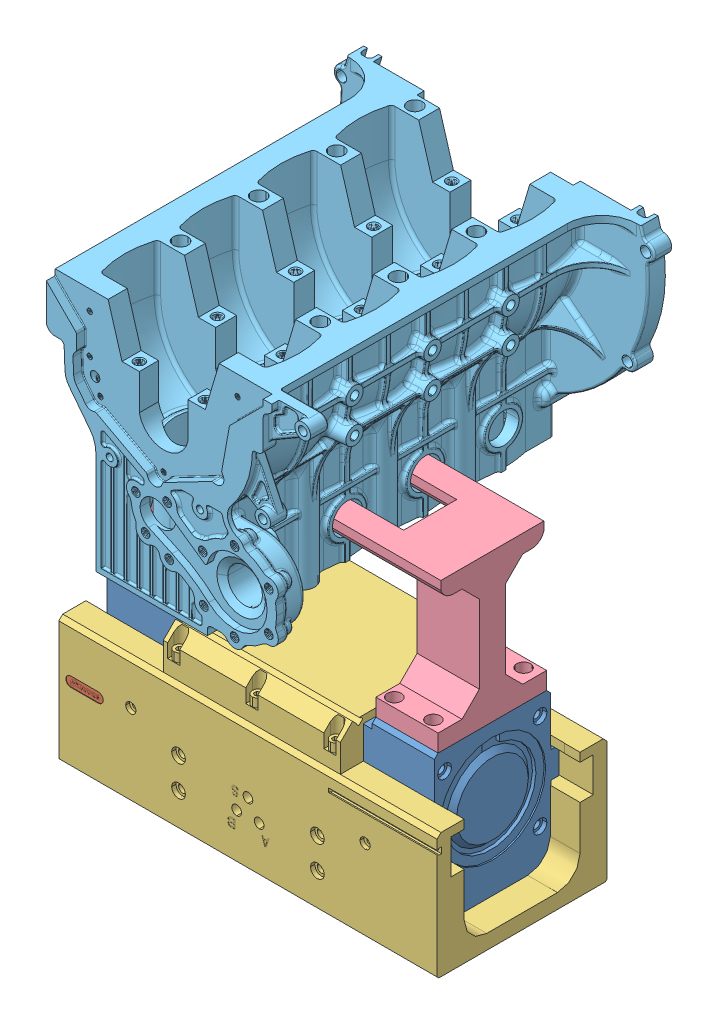
SolidWorks assembly SCHUNK_0302120_SPG_100_SDV_P__950ohne, configuration Default. Lengths in mm.
Overall size (436 582.06 410.5).
8 component instances, 6 part files, 25 mates.
Components (placement in the parent):
- SCHUNK_0302120_SPG_100_SDV_P__950ohne_3-1: SCHUNK_0302120_SPG_100_SDV_P__950ohne_3 [Default] at (-106.145 114.7 0.25) x (0 0 1) z (-1 0 0) size (154.2 173.7 174.7)
- SCHUNK_0302120_SPG_100_SDV_P__950ohne_3-2: SCHUNK_0302120_SPG_100_SDV_P__950ohne_3 [Default] at (96.355 114.7 0) x (0 0 -1) z (1 0 0) size (154.2 173.7 174.7)
- SCHUNK_0302120_SPG_100_SDV_P__950ohne_6-1: SCHUNK_0302120_SPG_100_SDV_P__950ohne_6 [Default] at (-188.35 86.7 97.3) x (-1 0 0) z (0 0 1) size (43 11 0.3)
- SCHUNK_0302120_SPG_100_SDV_P__950ohne_8-1: SCHUNK_0302120_SPG_100_SDV_P__950ohne_8 [Default] at origin size (436 191 196)
- griffa-1: griffa [Default] at (-157.645 356.6 45.25) x (0 0 -1) z (-1 0 0) size (125.01 170.71 140.85)
- griffa-2: griffa [Default] at (147.855 356.6 -45) x (0 0 1) z (1 0 0) size (125.01 170.71 140.85)
- XSR201_lavorato-1: XSR201_lavorato [Default] at (0 301.6755 0) x (0 1 0) z (-0.99865 0 -0.051938) size (110 140 140) (hidden)
- Head Motor-1: Head Motor [Default] at (-4.895 528.0542 135.25) x (-1 0 0) z (0 0 1) size (370.59 268.41 410.5)
Mates (geometry in assembly coordinates):
- Coincidente16: coincident anti-aligned: plane of SCHUNK_0302120_SPG_100_SDV_P__950ohne_3-1 through (-102 191.75 87.6) normal (1 0 0); plane of SCHUNK_0302120_SPG_100_SDV_P__950ohne_8-1 through (-102 145 150) normal (-1 0 0)
- Coincidente2: coincident anti-aligned: plane of SCHUNK_0302120_SPG_100_SDV_P__950ohne_3-2 through (102 191.75 -87.35) normal (-1 0 0); plane of SCHUNK_0302120_SPG_100_SDV_P__950ohne_8-1 through (102 192 150) normal (1 0 0)
- Coincidente6: coincident anti-aligned: plane of SCHUNK_0302120_SPG_100_SDV_P__950ohne_3-1 through (-193.495 134.45 67) normal (0 0 1); plane of SCHUNK_0302120_SPG_100_SDV_P__950ohne_8-1 through (200 182.4 67) normal (0 0 -1)
- Coincidente7: coincident anti-aligned: plane of SCHUNK_0302120_SPG_100_SDV_P__950ohne_3-2 through (183.705 187.3574 66.75) normal (0 0 1); plane of SCHUNK_0302120_SPG_100_SDV_P__950ohne_8-1 through (218 94.9 66.75) normal (0 0 -1)
- Coincidente8: coincident anti-aligned: plane of SCHUNK_0302120_SPG_100_SDV_P__950ohne_3-2 through (183.705 17.9 40.75) normal (0 -1 0); plane of SCHUNK_0302120_SPG_100_SDV_P__950ohne_8-1 through (218 17.9 40.75) normal (0 1 0)
- Coincidente9: coincident anti-aligned: plane of SCHUNK_0302120_SPG_100_SDV_P__950ohne_3-1 through (-193.495 17.9 -40.5) normal (0 -1 0); plane of SCHUNK_0302120_SPG_100_SDV_P__950ohne_8-1 through (218 17.9 40.75) normal (0 1 0)
- Coincidente10: coincident anti-aligned: plane of SCHUNK_0302120_SPG_100_SDV_P__950ohne_3-1 through (-193.495 191.6 62.7574) normal (0 1 0); plane of griffa-1 through (-157.645 191.6 45.25) normal (0 -1 0)
- Concentrico5: concentric anti-aligned: cylinder of SCHUNK_0302120_SPG_100_SDV_P__950ohne_3-1 through (-132.495 4.75 -51.75) axis (0 -1 0) radius 8; cylinder of griffa-1 through (-132.495 191.6 -51.75) axis (0 1 0) radius 8
- Concentrico6: concentric anti-aligned: cylinder of SCHUNK_0302120_SPG_100_SDV_P__950ohne_3-1 through (-177.495 4.75 52.25) axis (0 -1 0) radius 5.053; cylinder of griffa-1 through (-177.495 191.6 52.25) axis (0 1 0) radius 8
- Concentrico7: concentric anti-aligned: cylinder of SCHUNK_0302120_SPG_100_SDV_P__950ohne_3-2 through (167.705 4.75 -52) axis (0 -1 0) radius 8; cylinder of griffa-2 through (167.705 191.6 -52) axis (0 1 0) radius 8
- Coincidente11: coincident anti-aligned: plane of SCHUNK_0302120_SPG_100_SDV_P__950ohne_3-2 through (183.705 191.6 -62.5074) normal (0 1 0); plane of griffa-2 through (147.855 191.6 -45) normal (0 -1 0)
- Concentrico8: concentric anti-aligned: cylinder of SCHUNK_0302120_SPG_100_SDV_P__950ohne_3-2 through (122.705 4.75 52) axis (0 -1 0) radius 8; cylinder of griffa-2 through (122.705 191.6 52) axis (0 1 0) radius 8
- Parallelo1: parallel anti-aligned: plane of SCHUNK_0302120_SPG_100_SDV_P__950ohne_8-1 through (200 191 98) normal (0 1 0); plane of XSR201_lavorato-1 through (0 327.6 0) normal (0 -1 0)
- Concentrico9: concentric aligned: cylinder of SCHUNK_0302120_SPG_100_SDV_P__950ohne_8-1 through (0 8 0) axis (0 -1 0) radius 21.5; cylinder of XSR201_lavorato-1 through (0 301.6755 0) axis (0 -1 0) radius 23.5
- Tangente1: tangent anti-aligned: cylinder of griffa-2 through (112.005 356.6 45) axis (1 0 0) radius 15; plane of XSR201_lavorato-1 through (0 341.6 0) normal (0 1 0)
- Parallelo3: parallel anti-aligned: plane of SCHUNK_0302120_SPG_100_SDV_P__950ohne_8-1 through (200 191 98) normal (0 1 0); plane of Head Motor-1 through (-18.657 313.6542 -67.25) normal (0 -1 0)
- Parallelo2: parallel aligned: plane of SCHUNK_0302120_SPG_100_SDV_P__950ohne_8-1 through (218 0 0) normal (1 0 0); plane of Head Motor-1 through (62.105 356.6 45.25) normal (1 0 0)
- Concentrico10: concentric anti-aligned: cylinder of griffa-1 through (-52.645 356.6 45.25) axis (-1 0 0) radius 15; cylinder of Head Motor-1 through (-114.897 356.6 45.25) axis (1 0 0) radius 17.5
- Tangente2: tangent anti-aligned: plane of griffa-1 through (-67.65 356.6 45.25) normal (1 0 0); cylinder of Head Motor-1 through (-19.9 448.4542 45.25) axis (0 -1 0) radius 47.75
- Tangente4: tangent anti-aligned: plane of griffa-2 through (42.855 356.6 -45) normal (-1 0 0); cylinder of Head Motor-1 through (-4.895 448.4542 45.25) axis (0 -1 0) radius 47.75
- Tangente5: tangent anti-aligned: plane of griffa-1 through (-52.645 356.6 45.25) normal (1 0 0); cylinder of Head Motor-1 through (-4.895 448.4542 45.25) axis (0 -1 0) radius 47.75
- Coincidente17: coincident anti-aligned: plane of SCHUNK_0302120_SPG_100_SDV_P__950ohne_8-2 through (8.7761 216.2376 165) normal (0 0 -1); plane of SCHUNK_0302120_SPG_100_SDV_P__950ohne_3-3 through (-384.7189 168.2876 165) normal (0 0 1)
- Coincidente18: coincident: plane of SCHUNK_0302120_SPG_100_SDV_P__950ohne_8-2 through (-293.2239 178.8376 248) normal (-1 0 0); plane of SCHUNK_0302120_SPG_100_SDV_P__950ohne_3-3 through (-313.0189 225.5876 185.6) normal (1 0 0)
- Coincidente19: coincident anti-aligned: plane of SCHUNK_0302120_SPG_100_SDV_P__950ohne_8-2 through (26.7761 51.7376 138.75) normal (0 1 0); plane of SCHUNK_0302120_SPG_100_SDV_P__950ohne_3-3 through (-384.7189 51.7376 57.5) normal (0 -1 0)
- Blocca1: lock: unknown of SCHUNK_0302120_SPG_100_SDV_P__950ohne_3-2; unknown of SCHUNK_0302120_SPG_100_SDV_P__950ohne_8-1
